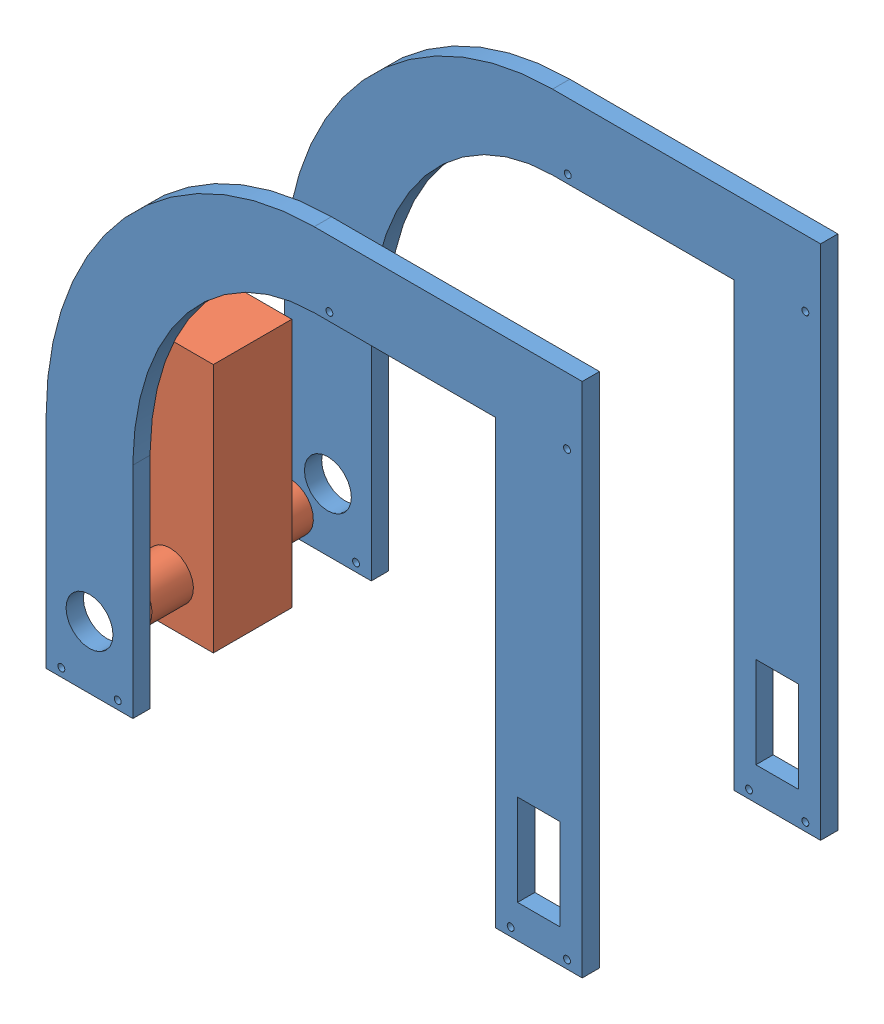
SolidWorks assembly Robot Assembly, configuration Default. Lengths in mm.
Overall size (246.38 237.42 117.48).
3 component instances, 2 part files, 6 mates.
Components (placement in the parent):
- outer_sides-1: outer_sides [Default] at (-53.9287 23.225 188.0528) size (246.38 237.42 7.94)
- outer_sides-2: outer_sides [Default] at (-53.9287 23.225 78.5153) size (246.38 237.42 7.94)
- dual motor-2: dual motor [Default] at (-53.9287 30.845 159.0333) x (0 0 -1) z (0 -1 0) size (74.17 39.88 114.81)
Mates (geometry in assembly coordinates):
- Coincident1: coincident: plane of assembly; plane of assembly; plane of outer_sides-1 through (69.2613 260.6475 188.0518) normal (0 1 0); plane of outer_sides-2 through (69.2613 260.6475 78.5143) normal (0 1 0)
- Coincident7: coincident: plane of assembly; plane of assembly; plane of outer_sides-1 through (192.4513 23.225 195.9903) normal (1 0 0); plane of outer_sides-2 through (192.4513 23.225 86.4528) normal (1 0 0)
- Distance3: distance = 101.6 mm: plane of assembly; plane of assembly; plane of outer_sides-2 through (-53.9287 23.225 86.4528) normal (0 0 1); plane of outer_sides-1 through (-53.9287 23.225 188.0528) normal (0 0 -1)
- Coincident9: coincident: plane of assembly; plane of assembly; plane of outer_sides-1 through (-53.9287 23.225 195.9903) normal (-1 0 0); plane of dual motor-2 through (-53.9287 30.845 159.0333) normal (-1 0 0)
- Distance4: distance = 44.45 mm: plane of assembly; plane of assembly; plane of dual motor-2 through (-14.0507 30.845 122.9653) normal (0 0 -1); plane of outer_sides-2 through (-53.9287 23.225 78.5153) normal (0 0 -1)
- Distance5: distance = 7.62 mm: plane of assembly; plane of assembly; plane of dual motor-2 through (-14.0507 30.845 159.0333) normal (0 -1 0); plane of outer_sides-1 through (-53.9287 23.225 195.9903) normal (0 -1 0)
